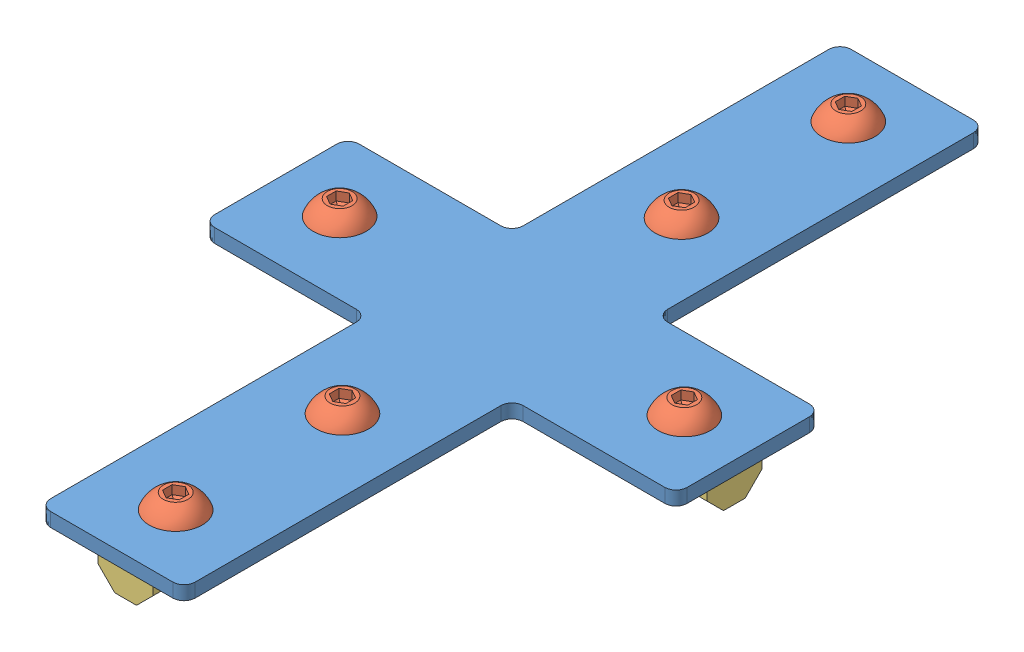
SolidWorks assembly 十字连接组, configuration 默认. Lengths in mm.
Overall size (85 12.75 144).
13 component instances, 3 part files, 30 mates.
Components (placement in the parent):
- 30_十字-1: 30_十字 [默认] at (-5.3811 -5.8102 144) size (85 2.5 144)
- hexagon socket button head screws gb-7: hexagon socket button head screws gb [GB_SOCKET_TYPE7 M5X10-N] at (-5.3811 -0.5602 204.5) x (0 -1 0) z (0 0 1) size (12.75 9.5 9.5)
- hexagon socket button head screws gb-8: hexagon socket button head screws gb [GB_SOCKET_TYPE7 M5X10-N] at (-5.3811 -0.5602 174.5) x (0 -1 0) z (0 0 1) size (12.75 9.5 9.5)
- hexagon socket button head screws gb-9: hexagon socket button head screws gb [GB_SOCKET_TYPE7 M5X10-N] at (25.6189 -0.5602 144) x (0 -1 0) z (0 0 1) size (12.75 9.5 9.5)
- hexagon socket button head screws gb-10: hexagon socket button head screws gb [GB_SOCKET_TYPE7 M5X10-N] at (-36.3811 -0.5602 144) x (0 -1 0) z (0 0 1) size (12.75 9.5 9.5)
- hexagon socket button head screws gb-11: hexagon socket button head screws gb [GB_SOCKET_TYPE7 M5X10-N] at (-5.3811 -0.5602 113.5) x (0 -1 0) z (0 0 1) size (12.75 9.5 9.5)
- hexagon socket button head screws gb-12: hexagon socket button head screws gb [GB_SOCKET_TYPE7 M5X10-N] at (-5.3811 -0.5602 83.5) x (0 -1 0) z (0 0 1) size (12.75 9.5 9.5)
- 30M5-1: 30M5 [默认] at (-5.3811 -10.1602 213.5) x (1 0 0) z (0 1 0) size (9.9 18 6.9)
- 30M5-2: 30M5 [默认] at (16.6189 -10.1602 144) x (0 0 1) z (0 1 0) size (9.9 18 6.9)
- 30M5-3: 30M5 [默认] at (-5.3811 -10.1602 92.5) x (1 0 0) z (0 1 0) size (9.9 18 6.9)
- 30M5-4: 30M5 [默认] at (-5.3811 -10.1602 122.5) x (1 0 0) z (0 1 0) size (9.9 18 6.9)
- 30M5-5: 30M5 [默认] at (-45.3811 -10.1602 144) x (0 0 1) z (0 1 0) size (9.9 18 6.9)
- 30M5-6: 30M5 [默认] at (-5.3811 -10.1602 183.5) x (1 0 0) z (0 1 0) size (9.9 18 6.9)
Mates (geometry in assembly coordinates):
- 同心8: concentric anti-aligned: cylinder of 30_十字-1 through (-5.3811 -3.3102 204.5) axis (0 -1 0) radius 3.5; cylinder of hexagon socket button head screws gb-7 through (-5.3811 -13.3102 204.5) axis (0 1 0) radius 2.5
- 同心9: concentric anti-aligned: cylinder of 30_十字-1 through (-5.3811 -3.3102 174.5) axis (0 -1 0) radius 3.5; cylinder of hexagon socket button head screws gb-8 through (-5.3811 -13.3102 174.5) axis (0 1 0) radius 2.5
- 同心10: concentric anti-aligned: cylinder of 30_十字-1 through (25.6189 -3.3102 144) axis (0 -1 0) radius 3.5; cylinder of hexagon socket button head screws gb-9 through (25.6189 -13.3102 144) axis (0 1 0) radius 2.5
- 同心11: concentric anti-aligned: cylinder of 30_十字-1 through (-36.3811 -3.3102 144) axis (0 -1 0) radius 3.5; cylinder of hexagon socket button head screws gb-10 through (-36.3811 -13.3102 144) axis (0 1 0) radius 2.5
- 同心12: concentric anti-aligned: cylinder of 30_十字-1 through (-5.3811 -3.3102 113.5) axis (0 -1 0) radius 3.5; cylinder of hexagon socket button head screws gb-11 through (-5.3811 -13.3102 113.5) axis (0 1 0) radius 2.5
- 同心13: concentric anti-aligned: cylinder of 30_十字-1 through (-5.3811 -3.3102 83.5) axis (0 -1 0) radius 3.5; cylinder of hexagon socket button head screws gb-12 through (-5.3811 -13.3102 83.5) axis (0 1 0) radius 2.5
- 重合8: coincident aligned: plane of 30_十字-1 through (-5.3811 -3.3102 144) normal (0 1 0); circle of hexagon socket button head screws gb-7
- 重合9: coincident aligned: plane of 30_十字-1 through (-5.3811 -3.3102 144) normal (0 1 0); circle of hexagon socket button head screws gb-8
- 重合10: coincident aligned: plane of 30_十字-1 through (-5.3811 -3.3102 144) normal (0 1 0); circle of hexagon socket button head screws gb-9
- 重合11: coincident aligned: plane of 30_十字-1 through (-5.3811 -3.3102 144) normal (0 1 0); circle of hexagon socket button head screws gb-10
- 重合12: coincident aligned: plane of 30_十字-1 through (-5.3811 -3.3102 144) normal (0 1 0); circle of hexagon socket button head screws gb-11
- 重合13: coincident aligned: plane of 30_十字-1 through (-5.3811 -3.3102 144) normal (0 1 0); circle of hexagon socket button head screws gb-12
- 重合14: coincident anti-aligned: plane of 30_十字-1 through (-5.3811 -5.8102 144) normal (0 -1 0); plane of 30M5-1 through (-8.2811 -5.8102 195.5) normal (0 1 0)
- 重合15: coincident anti-aligned: plane of 30_十字-1 through (-5.3811 -5.8102 144) normal (0 -1 0); plane of 30M5-6 through (-8.2811 -5.8102 165.5) normal (0 1 0)
- 重合16: coincident anti-aligned: plane of 30_十字-1 through (-5.3811 -5.8102 144) normal (0 -1 0); plane of 30M5-2 through (34.6189 -5.8102 141.1) normal (0 1 0)
- 重合17: coincident anti-aligned: plane of 30_十字-1 through (-5.3811 -5.8102 144) normal (0 -1 0); plane of 30M5-3 through (-8.2811 -5.8102 74.5) normal (0 1 0)
- 重合18: coincident anti-aligned: plane of 30_十字-1 through (-5.3811 -5.8102 144) normal (0 -1 0); plane of 30M5-4 through (-8.2811 -5.8102 104.5) normal (0 1 0)
- 重合19: coincident anti-aligned: plane of 30_十字-1 through (-5.3811 -5.8102 144) normal (0 -1 0); plane of 30M5-5 through (-27.3811 -5.8102 141.1) normal (0 1 0)
- 同心14: concentric aligned: cylinder of hexagon socket button head screws gb-12 through (-5.3811 -13.3102 83.5) axis (0 1 0) radius 2.5; cylinder of 30M5-3 through (-5.3811 -5.8102 83.5) axis (0 1 0) radius 2.1
- 同心15: concentric aligned: cylinder of hexagon socket button head screws gb-11 through (-5.3811 -13.3102 113.5) axis (0 1 0) radius 2.5; cylinder of 30M5-4 through (-5.3811 -5.8102 113.5) axis (0 1 0) radius 2.1
- 同心16: concentric aligned: cylinder of hexagon socket button head screws gb-10 through (-36.3811 -13.3102 144) axis (0 1 0) radius 2.5; cylinder of 30M5-5 through (-36.3811 -5.8102 144) axis (0 1 0) radius 2.1
- 同心17: concentric aligned: cylinder of hexagon socket button head screws gb-9 through (25.6189 -13.3102 144) axis (0 1 0) radius 2.5; cylinder of 30M5-2 through (25.6189 -5.8102 144) axis (0 1 0) radius 2.1
- 同心18: concentric aligned: cylinder of hexagon socket button head screws gb-8 through (-5.3811 -13.3102 174.5) axis (0 1 0) radius 2.5; cylinder of 30M5-6 through (-5.3811 -5.8102 174.5) axis (0 1 0) radius 2.1
- 同心19: concentric aligned: cylinder of hexagon socket button head screws gb-7 through (-5.3811 -13.3102 204.5) axis (0 1 0) radius 2.5; cylinder of 30M5-1 through (-5.3811 -5.8102 204.5) axis (0 1 0) radius 2.1
- 平行1: parallel aligned: plane of 30_十字-1 through (-18.3811 -3.3102 157) normal (-1 0 0); plane of 30M5-1 through (-10.3311 -7.6102 195.5) normal (-1 0 0)
- 平行2: parallel aligned: plane of 30_十字-1 through (-18.3811 -3.3102 157) normal (-1 0 0); plane of 30M5-6 through (-10.3311 -7.6102 165.5) normal (-1 0 0)
- 平行3: parallel anti-aligned: plane of 30_十字-1 through (7.6189 -3.3102 157) normal (0 0 1); plane of 30M5-2 through (34.6189 -7.6102 139.05) normal (0 0 -1)
- 平行4: parallel aligned: plane of 30_十字-1 through (-18.3811 -3.3102 72) normal (-1 0 0); plane of 30M5-4 through (-10.3311 -7.6102 104.5) normal (-1 0 0)
- 平行5: parallel aligned: plane of 30_十字-1 through (-18.3811 -3.3102 72) normal (-1 0 0); plane of 30M5-3 through (-10.3311 -7.6102 74.5) normal (-1 0 0)
- 平行6: parallel anti-aligned: plane of 30_十字-1 through (-47.8811 -3.3102 157) normal (0 0 1); plane of 30M5-5 through (-27.3811 -7.6102 139.05) normal (0 0 -1)
